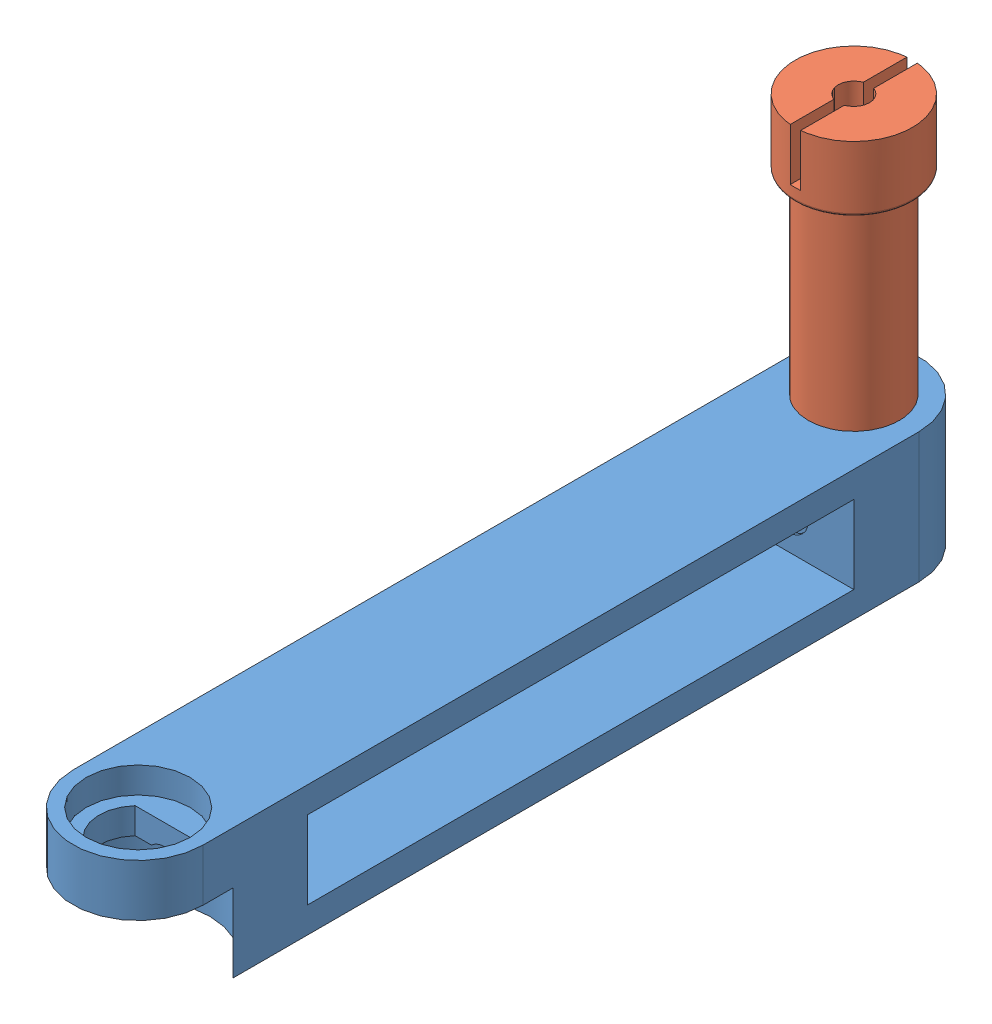
SolidWorks assembly Arm1Assembly, configuration Default. Lengths in mm.
Overall size (50 150 325).
2 component instances, 2 part files, 4 mates.
Components (placement in the parent):
- Arm1-1: Arm1 [Single Assem] at (0 -150 0) x (0 0 1) z (-1 0 0) size (325 50 50)
- Joint1RotaryShaft-1: Joint1RotaryShaft [Default] at origin size (45 150 45)
Mates (geometry in assembly coordinates):
- Concentric1: concentric anti-aligned: cylinder of Arm1-1 through (0 -99.999 0) axis (0 -1 0) radius 17.5; cylinder of Joint1RotaryShaft-1 through (0 -150 0) axis (0 1 0) radius 17.5
- Coincident1: coincident anti-aligned: plane of Arm1-1 through (9.0139 -99.999 15) normal (0 0 -1); plane of Joint1RotaryShaft-1 through (0 -100 15) normal (0 0 1)
- LimitDistance1: limit distance = 15 mm anti-aligned: plane of Joint1RotaryShaft-1 through (-6.8016 103.8589 233.0068) normal (0 -1 0); plane of Arm1-1 through (-6.8016 103.8589 233.0068) normal (0 1 0)
- Concentric4: concentric aligned: circle of Arm1-1; circle of Joint1RotaryShaft-1
